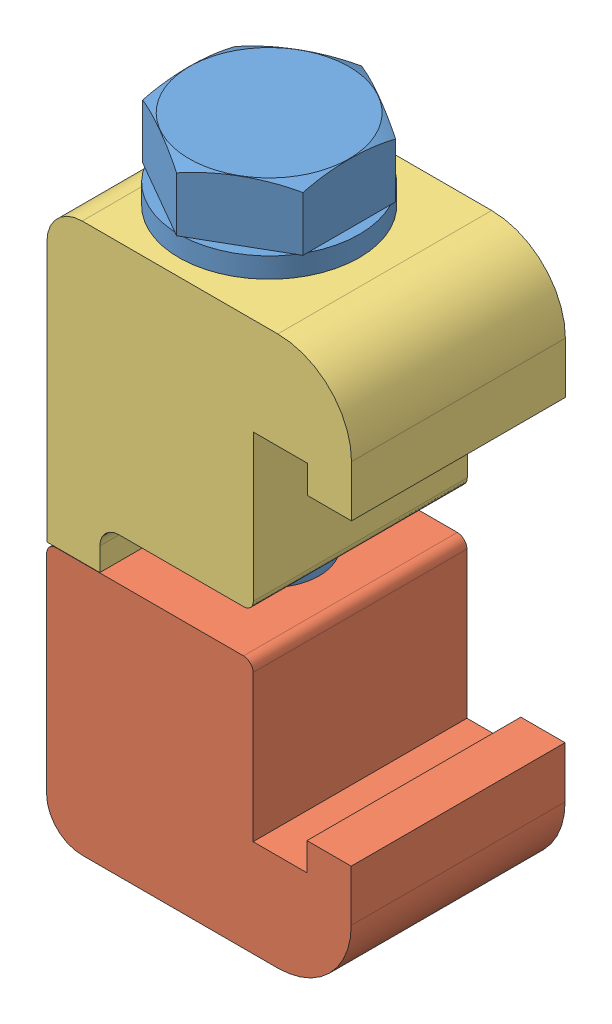
SolidWorks assembly 802000, configuration Default. Lengths in mm.
Overall size (24.13 50.61 16.97).
3 component instances, 3 part files, 6 mates.
Components (placement in the parent):
- SUB-1: SUB [Default] at (-2.5622 23.7937 50.7716) size (14.68 49.98 14.68)
- 980220-1: 980220 [Default] at (21.4154 4.1341 33.8552) x (-1 0 0) z (0 0 1) size (24.13 20.07 16.94)
- 980230-1: 980230 [Default] at (21.4154 47.6189 50.7716) x (-1 0 0) z (0 0 -1) size (24.13 23.42 16.94)
Mates (geometry in assembly coordinates):
- Concentric1: concentric anti-aligned: cylinder of SUB-1 through (6.4294 49.2191 42.3134) axis (0 -1 0) radius 3.9688; cylinder of 980230-1 through (6.4294 47.6189 42.3134) axis (0 1 0) radius 4.191
- Coincident1: coincident anti-aligned: plane of SUB-1 through (6.4294 47.6189 42.3134) normal (0 -1 0); plane of 980230-1 through (21.4154 47.6189 33.8298) normal (0 1 0)
- Concentric2: concentric aligned: cylinder of SUB-1 through (6.4294 49.2191 42.3134) axis (0 -1 0) radius 3.9688; cylinder of 980220-1 through (6.4294 4.1341 42.3134) axis (0 -1 0) radius 3.4
- Coincident2: coincident anti-aligned: plane of 980220-1 through (-2.7146 24.2001 50.797) normal (0 1 0); plane of 980230-1 through (-2.7146 24.2001 33.8298) normal (0 -1 0)
- Coincident3: coincident aligned: plane of 980220-1 through (-2.7146 4.1341 50.797) normal (-1 0 0); plane of 980230-1 through (-2.7146 47.6189 33.8298) normal (-1 0 0)
- Parallel1: parallel aligned: plane of 980230-1 through (21.4154 47.6189 50.7716) normal (0 0 1)
